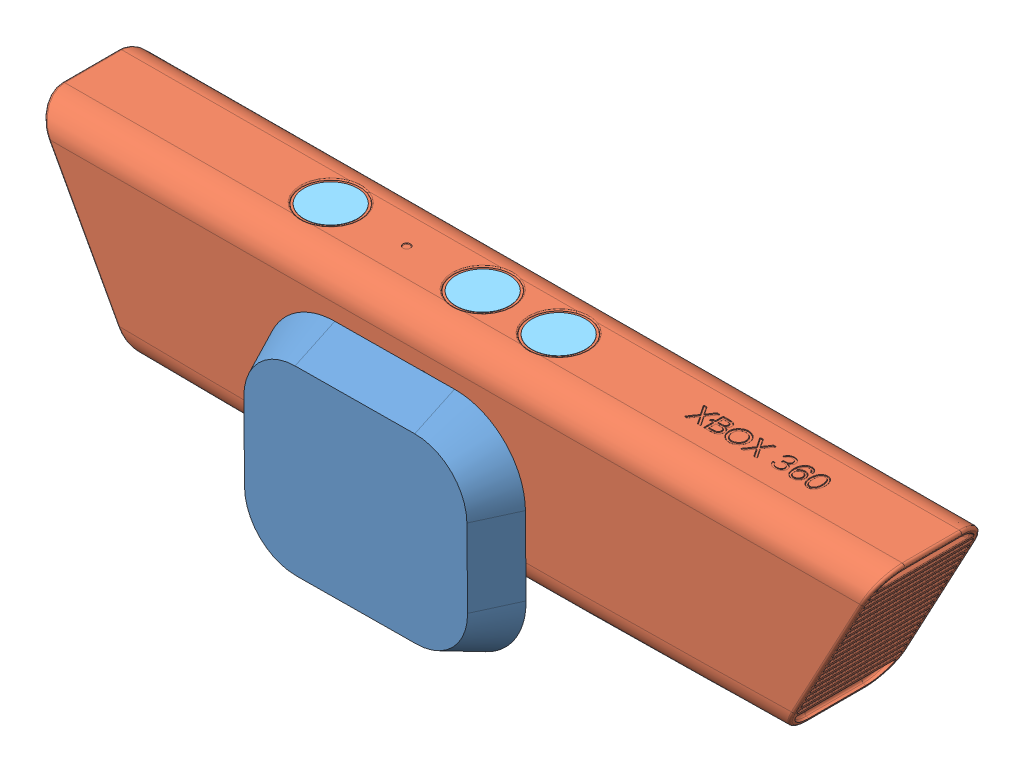
SolidWorks assembly kinect assembly, configuration Default. Lengths in mm.
Overall size (281.71 76.12 72.2).
8 component instances, 5 part files, 10 mates.
Components (placement in the parent):
- kinect base-1: kinect base [Default] at (-20.9932 -5.9594 15.1266) x (-0.999962 -0.008727 0) z (0 0 1) size (89.59 75.34 31.49)
- kinect-1: kinect [Default] at (-162.3863 24.8348 -4.821) x (0.999994 0.003403 0) z (0 0 -1) size (281.5 63.66 39.74)
- kinect pivot-2: kinect pivot [Default] at (-20.9932 -5.9594 11.8478) x (0 1 0) z (0 0 -1) size (25.4 25.4 32.54)
- kinect middle lightbulb-1: kinect middle lightbulb [Default] at (-30.8691 22.0262 -23.871) x (0.990755 0.003371 0.135623) z (-0.003403 0.999994 0) size (3.17 3.17 1.59)
- kinect middle lightbulb-2: kinect middle lightbulb [Default] at (-5.4695 22.1937 -23.871) x (0.999071 0.003399 0.042963) z (-0.003403 0.999994 0) size (3.17 3.17 1.59)
- kinect lens cover-1: kinect lens cover [Default] at (-81.6785 24.7125 -23.871) x (0.999994 0.003403 -0.000631) z (-0.003403 0.999994 0) size (17.78 17.78 0.1)
- kinect lens cover-2: kinect lens cover [Default] at (-30.8792 24.9846 -23.871) x (0.999994 0.003403 -0.000388) z (0.003403 -0.999994 0) size (17.78 17.78 0.1)
- kinect lens cover-3: kinect lens cover [Default] at (-5.4793 25.071 -23.871) x (0.999994 0.003403 -0.000677) z (0.003403 -0.999994 0) size (17.78 17.78 0.1)
Mates (geometry in assembly coordinates):
- Concentric3: concentric aligned: circle of kinect base-1; circle of kinect pivot-2
- Concentric4: concentric anti-aligned: circle of kinect-1; circle of kinect pivot-2
- Coincident8: coincident anti-aligned: plane of kinect-1 through (-20.9932 -5.9594 -7.996) normal (0 0 1); plane of kinect pivot-2 through (-20.9932 -5.9594 -7.996) normal (0 0 -1)
- Concentric5: concentric aligned: circle of kinect-1; circle of kinect middle lightbulb-1
- Coincident10: coincident aligned: circle of kinect-1; circle of kinect middle lightbulb-2
- Coincident11: coincident aligned: circle of kinect-1; circle of kinect lens cover-1
- Coincident12: coincident: plane of kinect-1 through (-30.8788 24.8854 -23.871) normal (-0.003403 0.999994 0); plane of kinect lens cover-2 through (-30.8788 24.8854 -23.871) normal (0.003403 -0.999994 0)
- Concentric8: concentric anti-aligned: circle of kinect-1; circle of kinect lens cover-2
- Coincident13: coincident: plane of kinect-1 through (-5.479 24.9718 -23.871) normal (-0.003403 0.999994 0); plane of kinect lens cover-3 through (-5.479 24.9718 -23.871) normal (0.003403 -0.999994 0)
- Concentric9: concentric anti-aligned: circle of kinect-1; circle of kinect lens cover-3
